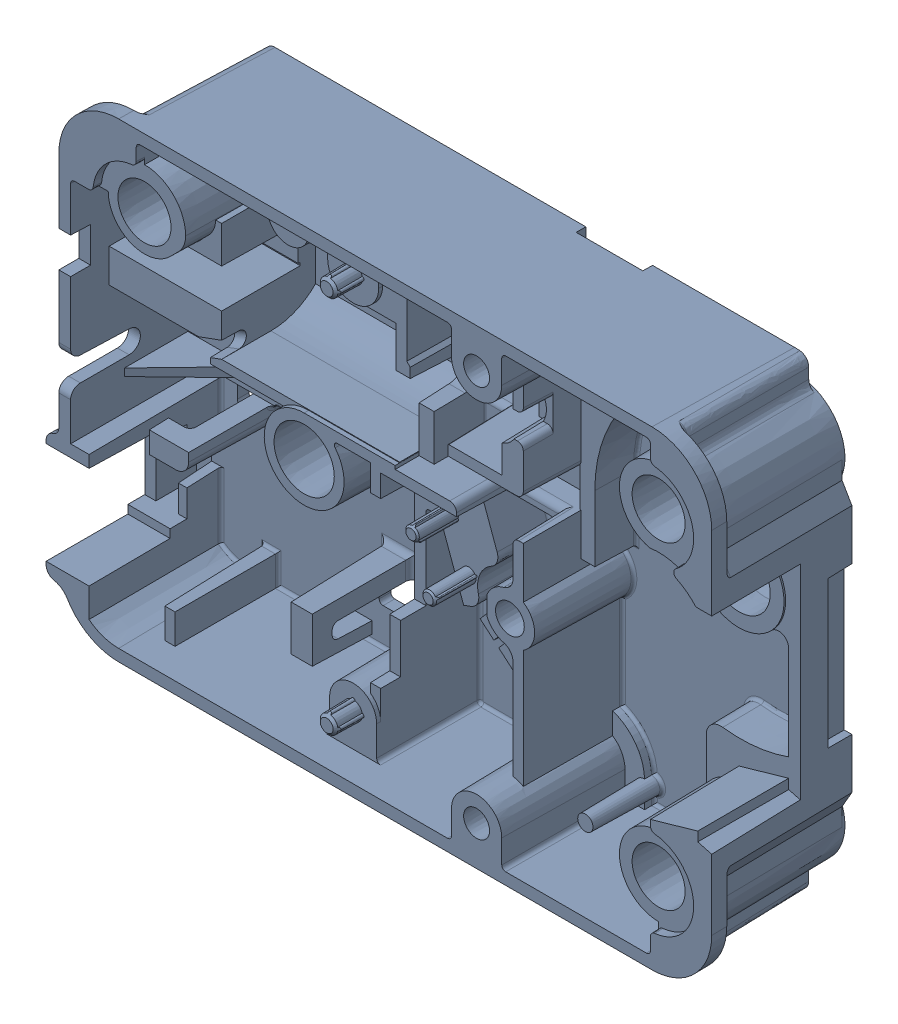
SolidWorks assembly 706001, configuration Default. Lengths in mm.
Overall size (86.28 61.13 19.4).
2 component instances, 2 part files, 2 mates.
Components (placement in the parent):
- 705029-1: 705029 [Default] at origin size (86.28 61.13 18.87)
- 2307-1: 2307 [Default] at (-6.0706 3.9688 2.1081) x (0 0.318486 0.947927) z (1 0 0) size (4.76 4.76 22.23)
Mates (geometry in assembly coordinates):
- Width1: width aligned: plane of 705029-1 through (-5.9055 0 2.032) normal (-0.999962 0 -0.008727); plane of 2307-1 through (-28.4607 0 2.032) normal (0.999962 0 -0.008727); plane of 705029-1 through (-6.0706 3.9688 2.1081) normal (1 0 0); plane of 2307-1 through (-28.2956 3.9688 2.1081) normal (-1 0 0)
- Concentric1: concentric anti-aligned: cylinder of 705029-1 through (-5.9055 3.9688 2.1081) axis (-1 0 0) radius 2.3813; cylinder of 2307-1 through (-28.2956 3.9688 2.1081) axis (1 0 0) radius 2.3813
